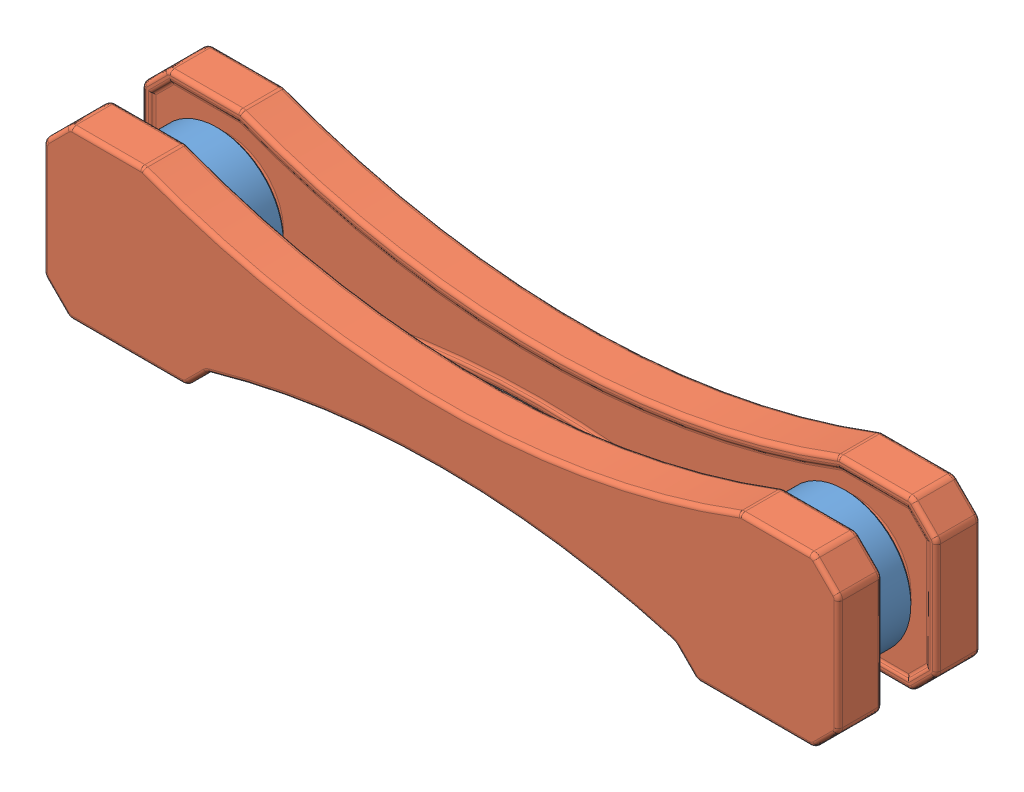
SolidWorks assembly Printable Spool Holder, configuration Default. Lengths in mm.
Overall size (95 20 16.98).
5 component instances, 3 part files, 8 mates.
Components (placement in the parent):
- 0250ID - 0625OD - 0196W-1: 0250ID - 0625OD - 0196W [Default] at (37.5 0 -3.4892) x (0 0 1) z (-0.999454 -0.033038 0) size (4.98 15.88 15.88)
- 0250ID - 0625OD - 0196W-2: 0250ID - 0625OD - 0196W [Default] at (-37.5 0 -3.4892) x (0 0 1) z (-0.999454 -0.033038 0) size (4.98 15.88 15.88)
- Printable Spool Holder-2: Printable Spool Holder [Default] at origin size (95 20 16.98)
- No 4 x 0500L PANHT SS Sheet Metal Type II B-1: No 4 x 0500L PANHT SS Sheet Metal Type II B [PANHTS 0.112-24-type II-B-0.8125-N] at (37.5 0 -11.2056) x (0 0 1) z (-0.892775 0.450503 0) size (13.92 5.56 5.56)
- No 4 x 0500L PANHT SS Sheet Metal Type II B-2: No 4 x 0500L PANHT SS Sheet Metal Type II B [PANHTS 0.112-24-type II-B-0.8125-N] at (-37.5 0 -11.2056) x (0 0 1) z (-0.728629 0.684909 0) size (13.92 5.56 5.56)
Mates (geometry in assembly coordinates):
- Concentric5: concentric anti-aligned: cylinder of 0250ID - 0625OD - 0196W-1 through (37.5 0 -3.4892) axis (0 0 -1) radius 3.175; cylinder of Printable Spool Holder-2 through (37.5 0 -3.25) axis (0 0 1) radius 3.175
- Coincident3: coincident anti-aligned: plane of 0250ID - 0625OD - 0196W-1 through (37.3448 4.6964 -1) normal (0 0 1); plane of Printable Spool Holder-2 through (37.5 0 -1) normal (0 0 -1)
- Concentric6: concentric anti-aligned: cylinder of 0250ID - 0625OD - 0196W-2 through (-37.5 0 -3.4892) axis (0 0 -1) radius 3.175; cylinder of Printable Spool Holder-2 through (-37.5 0 -3.25) axis (0 0 1) radius 3.175
- Coincident4: coincident anti-aligned: plane of 0250ID - 0625OD - 0196W-2 through (-37.6552 4.6964 -1) normal (0 0 1); plane of Printable Spool Holder-2 through (-37.5 0 -1) normal (0 0 -1)
- Concentric7: concentric aligned: cylinder of Printable Spool Holder-2 through (37.5 0 0.7971) axis (0 0 -1) radius 1.6; cylinder of No 4 x 0500L PANHT SS Sheet Metal Type II B-1 through (37.5 0 -11.2056) axis (0 0 -1) radius 1.4224
- Coincident5: coincident anti-aligned: plane of Printable Spool Holder-2 through (37.5 0 -9.4784) normal (0 0 -1); plane of No 4 x 0500L PANHT SS Sheet Metal Type II B-1 through (38.1408 1.2699 -9.4784) normal (0 0 1)
- Concentric8: concentric aligned: cylinder of Printable Spool Holder-2 through (-37.5 0 0.7971) axis (0 0 -1) radius 1.6; cylinder of No 4 x 0500L PANHT SS Sheet Metal Type II B-2 through (-37.5 0 -11.2056) axis (0 0 -1) radius 1.4224
- Coincident6: coincident anti-aligned: plane of Printable Spool Holder-2 through (-37.5 0 -9.4784) normal (0 0 -1); plane of No 4 x 0500L PANHT SS Sheet Metal Type II B-2 through (-36.5258 1.0364 -9.4784) normal (0 0 1)
